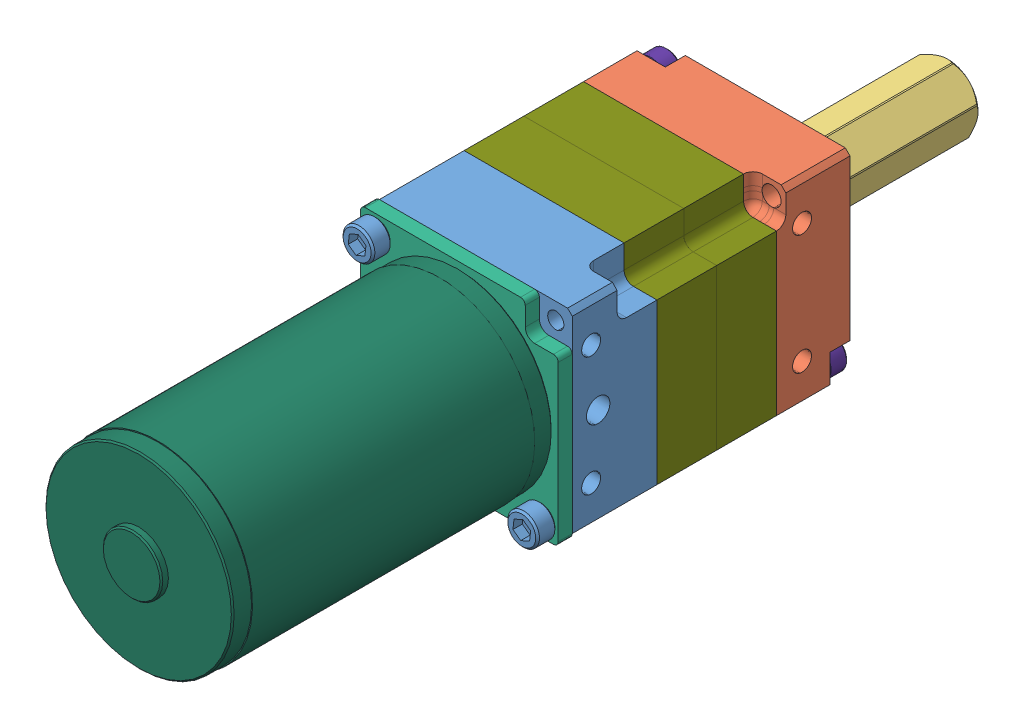
SolidWorks assembly VEXpro-VersaPlanetary-2stage-with-BAG, configuration Default. Lengths in mm.
Overall size (49.3 49.3 173.58).
42 component instances, 24 part files, 0 mates.
Components (placement in the parent):
- 217-2625-001 Rev1-1: 217-2625-001 Rev1 [Default] at origin size (42 42 18)
- 217-2625-002 Rev1-1: 217-2625-002 Rev1 [Default] at (0 0 -29.4) size (42 42 17.13)
- 217-2625-003 Rev1-1: 217-2625-003 Rev1 [Default] at (0 0 -43.6478) x (0.966651 -0.256095 0) z (0 0 -1) size (17 17 64.12)
- 217-2625-009 Rev1-1: 217-2625-009 Rev1 [Default] at (0 0 -3.48) x (-0.609619 0.792694 0) z (0 0 -1) size (18 18 13)
- 217-2625-100-1: 217-2625-100 [Default] at (0 0 -18.8454) x (0.784104 -0.62063 0) z (0 0 1) size (39.26 38.9 12.7)
  - 217-2625-008 Rev1-1: 217-2625-008 Rev1 [Default] at origin size (34.7 34.7 4.7)
  - 217-2625-010 Rev1-1: 217-2625-010 Rev1 [Default] at (0 10.193 3.65) x (0.999813 0.019336 0) z (0 0 1) size (4 4 12)
  - 217-2625-010 Rev1-2: 217-2625-010 Rev1 [Default] at (8.691 -5.3258 3.65) size (4 4 12)
  - 217-2625-010 Rev1-3: 217-2625-010 Rev1 [Default] at (-8.691 -5.3258 3.65) size (4 4 12)
  - 217-2625-005 Rev1_Planet_Revolving_Follower01-1: 217-2625-005 Rev1_Planet_Revolving_Follower01 [Default] at (8.691 -5.3258 6.35) x (0.932816 0.360354 0) z (0 0 1) size (16.91 16.92 8)
  - 217-2625-005 Rev1_Planet_Revolving_Follower01-2: 217-2625-005 Rev1_Planet_Revolving_Follower01 [Default] at (-8.691 -5.3258 6.35) x (-0.932788 -0.360426 0) z (0 0 1) size (16.91 16.92 8)
  - 217-2625-005 Rev1_Planet_Revolving_Follower01-3: 217-2625-005 Rev1_Planet_Revolving_Follower01 [Default] at (0 10.193 6.35) x (0.893583 0.448898 0) z (0 0 1) size (16.91 16.92 8)
- 217-2625-007 Rev1_Sun_Driver01-1: 217-2625-007 Rev1_Sun_Driver01 [Default] at (0 0 -11.5575) x (0.564419 -0.825488 0) z (0 0 1) size (14.49 14.49 12.72)
- 217-2742-1: 217-2742 [Default] at (0 0 -51.4002) x (0 0 1) z (-0.997393 0.072165 0) size (7 28 28)
- 217-2742-2: 217-2742 [Default] at (0 0 -43.1002) x (0 0 1) z (-1 0 0) size (7 28 28)
- 217-2741-1: 217-2741 [Default] at (0 0 -7) x (0 0 1) z (-0.951311 0.308231 0) size (5 26 26)
- TRUARC-MSH-15_98541A410-1: TRUARC-MSH-15_98541A410 [Default] at (0 0 -35.4954) x (0 0 -1) z (0.980859 -0.194721 0) size (1 19.6 17.4)
- SPRGW0856-1102-012_9714K62-1: SPRGW0856-1102-012_9714K62 [Default] at (0 0 -44.1002) x (-0.695225 0.718792 0) z (-0.718792 -0.695225 0) size (29.09 5.11 30.79)
- SSS1032-0125ZB_94105A824-1: SSS1032-0125ZB_94105A824 [Default] at (5.4759 4.2112 1.995) x (-0.605001 0.78669 -0.122849) z (0.792694 0.609619 0) size (4.83 4.84 3.3)
- TRUARC-5103-68_97414A675_grv-1: TRUARC-5103-68_97414A675_grv [Default] at (1.1965 0.0349 -1.3834) x (0 0 -1) z (-0.029125 0.999576 0) size (1.07 15.49 20.19)
- 217-3351-1: 217-3351 [Default] at (0 0 10.675) x (0 -1 0) z (0 0 -1) size (40.4 40.4 81.5)
- 217-2816-001 Rev1-1: 217-2816-001 Rev1 [Default] at (0 0 -29.55) x (1 0 0) z (0 0 -1) size (42 42 14.5)
- SSA_SSA0832-1750ZC-1: SSA_SSA0832-1750ZC [Default] at (-17.5 17.5 -47.261) x (-0.769034 -0.639207 0) z (0.639207 -0.769034 0) size (6.73 48.51 6.73)
- SSA_SSA0832-1750ZC-2: SSA_SSA0832-1750ZC [Default] at (17.5 -17.5 -47.261) x (0.162252 0.986749 0) z (-0.986749 0.162252 0) size (6.73 48.51 6.73)
- 217-2625-011 Rev1-1: 217-2625-011 Rev1 [Default] at (0 0 1.37) x (-0.792694 -0.609619 0) z (-0.609619 0.792694 0) size (8.01 7.5 7.94)
- SSA_SSA0832-0500ZC-1: SSA_SSA0832-0500ZC [Default] at (-17.5 17.5 10.675) x (0.592766 0.805375 0) z (0.805375 -0.592766 0) size (6.73 16.76 6.73)
- SSA_SSA0832-0500ZC-2: SSA_SSA0832-0500ZC [Default] at (17.5 -17.5 10.675) x (-0.592766 -0.805375 0) z (-0.805375 0.592766 0) size (6.73 16.76 6.73)
- SSHCM004_SSHCM004070010C-1: SSHCM004_SSHCM004070010C [Default] at (0 -12.5 7.5) x (-0.451598 -0.892221 0) z (0.892221 -0.451598 0) size (7 14 7)
- SSHCM004_SSHCM004070010C-2: SSHCM004_SSHCM004070010C [Default] at (0 12.5 7.5) x (-0.447517 -0.894275 0) z (0.894275 -0.447517 0) size (7 14 7)
- 217-2816-001 Rev1-2: 217-2816-001 Rev1 [Default] at (0 0 -16.85) x (1 0 0) z (0 0 -1) size (42 42 14.5)
- 217-2818 Rev1-1: 217-2818 Rev1 [Default] at (0 0 -31.5454) size (49.07 49.07 17.4)
  - 217-2725-001 Rev1_24t Sun-1: 217-2725-001 Rev1_24t Sun [Default] at (0 0 8.7) size (14.45 14.45 12.7)
  - 217-2725-002 Rev1_24t Planet-1: 217-2725-002 Rev1_24t Planet [Default] at (-12.089 0 6.35) x (-0.130526 0.991445 0) z (0 0 -1) size (13.17 13.15 8)
  - 217-2724-002 Rev1-1: 217-2724-002 Rev1 [Default] x (0.707107 -0.707107 0) z (0 0 -1) size (34.7 34.7 4.7)
  - 217-2625-010 Rev1-1: 217-2625-010 Rev1 [Default] at (-12.089 0 3.65) x (0.971612 -0.236582 0) z (0 0 1) size (4 4 12)
  - 217-2725-002 Rev1_24t Planet-2: 217-2725-002 Rev1_24t Planet [Default] at (0 -12.089 6.35) x (-0.991445 -0.130526 0) z (0 0 -1) size (13.17 13.15 8)
  - 217-2725-002 Rev1_24t Planet-3: 217-2725-002 Rev1_24t Planet [Default] at (12.089 0 6.35) x (0.130526 -0.991445 0) z (0 0 -1) size (13.17 13.15 8)
  - 217-2725-002 Rev1_24t Planet-4: 217-2725-002 Rev1_24t Planet [Default] at (0 12.089 6.35) x (0.991445 0.130526 0) z (0 0 -1) size (13.17 13.15 8)
  - 217-2625-010 Rev1-2: 217-2625-010 Rev1 [Default] at (0 -12.089 3.65) x (0.236582 0.971612 0) z (0 0 1) size (4 4 12)
  - 217-2625-010 Rev1-3: 217-2625-010 Rev1 [Default] at (12.089 0 3.65) x (-0.971612 0.236582 0) z (0 0 1) size (4 4 12)
  - 217-2625-010 Rev1-4: 217-2625-010 Rev1 [Default] at (0 12.089 3.65) x (-0.236582 -0.971612 0) z (0 0 1) size (4 4 12)
- 217-2822-003 Rev4-1: 217-2822-003 Rev4 [Default] at (0 0 9) x (0 -1 0) z (0 0 1) size (42 42 4.8)
